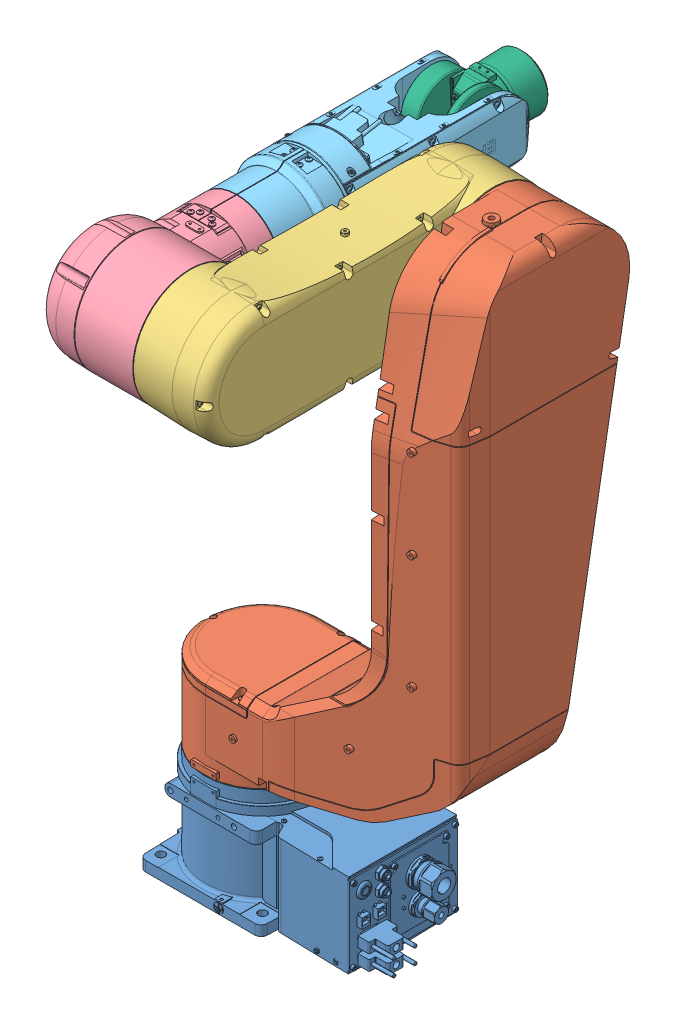
SolidWorks assembly N6-1000SR_step, configuration Default. Lengths in mm.
Overall size (439.24 963.55 702.5).
7 component instances, 7 part files, 18 mates.
Components (placement in the parent):
- BASE_1-1: BASE_1 [Default] at (0 168 0) x (-1 0 0) z (0 0 -1) size (378.1 251 200.8)
- ARM1-1: ARM1 [Default] at (0 166 0) x (-1 0 0) z (0 0 -1) size (429.24 796 333.69)
- ARM2-1: ARM2 [Default] at (216 867 -150) x (-1 0 0) z (0 1 0) size (213.01 535 193.09)
- ARM3-1: ARM3 [Default] at (86 867 200) x (-1 0 0) z (0 1 0) size (166 294.3 182.18)
- ARM4-1: ARM4 [Default] at (0 867 40) x (-1 0 0) z (0 1 0) size (155.1 402.5 156.68)
- ARM5-1: ARM5 [Default] at (0 867 -407) x (-1 0 0) z (0 1 0) size (88.22 146.2 100)
- ARM6-1: ARM6 [Default] at (0 867 -410) x (-1 0 0) z (0 1 0) size (79 23 79)
Mates (geometry in assembly coordinates):
- Distance1: distance = 1 mm anti-aligned: plane of BASE_1-1 through (0 168 0) normal (0 1 0); plane of ARM1-1 through (-90 169 0) normal (0 -1 0)
- Concentric1: concentric aligned: cylinder of BASE_1-1 through (0 106 0) axis (0 1 0) radius 88; cylinder of ARM1-1 through (0 166 0) axis (0 1 0) radius 87
- Distance2: distance = 1 mm anti-aligned: plane of ARM1-1 through (214 957 -150) normal (-1 0 0); plane of ARM2-1 through (213 867 -240.3) normal (1 0 0)
- Concentric2: concentric aligned: cylinder of ARM1-1 through (214 867 -150) axis (1 0 0) radius 90; cone of ARM2-1 through (182.7186 867 -150) axis (1 0 0)
- Distance3: distance = 1 mm anti-aligned: plane of ARM3-1 through (86 867 200) normal (1 0 0); plane of ARM2-1 through (87 867 290.3) normal (-1 0 0)
- Concentric3: concentric anti-aligned: cone of ARM2-1 through (150.07 867 200) axis (-1 0 0); cylinder of ARM3-1 through (-80 867 200) axis (1 0 0) radius 90.3
- Distance4: distance = 1 mm anti-aligned: plane of ARM4-1 through (0 798 40) normal (0 0 1); plane of ARM3-1 through (66.8 867 41) normal (0 0 -1)
- Concentric4: concentric aligned: cylinder of ARM3-1 through (0 867 109.7) axis (0 0 -1) radius 69; cylinder of ARM4-1 through (0 867 40) axis (0 0 -1) radius 69
- Concentric8: concentric aligned: cylinder of ARM4-1 through (29 867 -310) axis (1 0 0) radius 37.25; cylinder of ARM5-1 through (28 867 -310) axis (1 0 0) radius 34.5
- Distance7: distance = 3 mm aligned: plane of ARM6-1 through (-11.3 867 -410) normal (0 0 -1); plane of ARM5-1 through (0 867 -407) normal (0 0 -1)
- Concentric9: concentric aligned: cylinder of ARM5-1 through (0 867 -410) axis (0 0 1) radius 39.5; cylinder of ARM6-1 through (0 867 -410) axis (0 0 1) radius 39.5
- Distance8: distance = 1 mm anti-aligned: plane of ARM4-1 through (29 867 -274) normal (-1 0 0); plane of ARM5-1 through (28 908 -348.9711) normal (1 0 0)
- Angle1: planar angle = 0 rad aligned: plane of BASE_1-1 through (0 168 0) normal (0 0 -1); plane of ARM1-1 through (0 166 0) normal (0 0 -1)
- Angle2: planar angle = 0 rad aligned: plane of ARM1-1; plane of ARM2-1 through (216 867 -150) normal (0 1 0)
- Angle3: planar angle = 0 rad aligned: plane of ARM3-1 through (86 867 200) normal (0 1 0); plane of ARM4-1 through (0 867 40) normal (0 1 0)
- Angle4: planar angle = 0 rad aligned: plane of ARM5-1 through (0 867 -407) normal (0 1 0); plane of ARM6-1 through (0 867 -410) normal (0 1 0)
- Angle5: planar angle = 0 rad aligned: plane of ARM2-1 through (216 867 -150) normal (0 1 0); plane of ARM3-1 through (86 867 200) normal (0 1 0)
- Angle6: planar angle = 0 rad aligned: plane of ARM5-1 through (0 867 -407) normal (0 1 0); plane of ARM4-1 through (0 867 40) normal (0 1 0)
